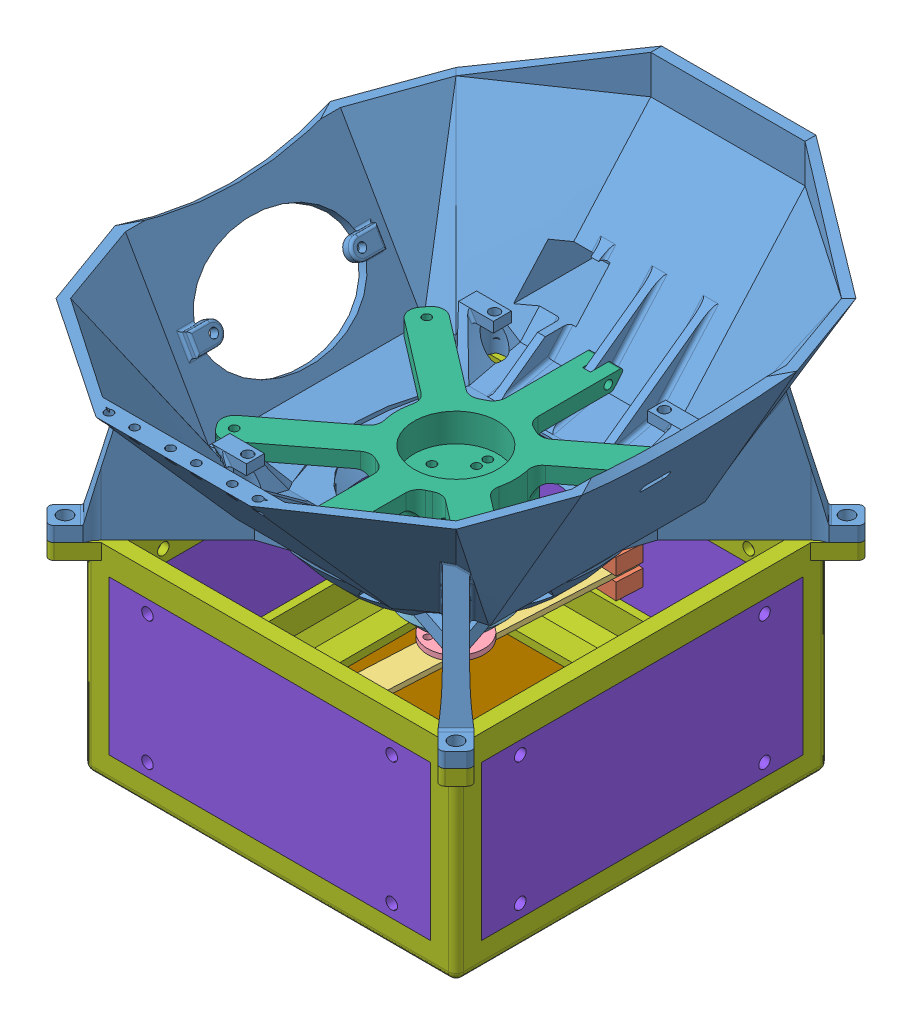
SolidWorks assembly TopFrameWithFlywheel_V1_CN, configuration Défaut. Lengths in mm.
Overall size (181.59 173.79 220.01).
16 component instances, 9 part files, 20 mates.
Components (placement in the parent):
- TopFrame_V1_CN_InProgress-1: TopFrame_V1_CN_InProgress [Default] at origin size (181.59 93.79 220.01)
- Flywheel_CN_V2-1: Flywheel_CN_V2 [Default] at (-0.05 -30.5 0) x (-0.998597 0 -0.052958) z (0 -1 0) size (15 125 14.7)
  - PlaqueEpaisseFlywheel_CN_V2-1: PlaqueEpaisseFlywheel_CN_V2 [Default] at (0 57.5 1) size (15 10 6.35)
  - PlaqueMinceFlywheel_CN_V2-1: PlaqueMinceFlywheel_CN_V2 [Default] x (-1 0 0) z (0 0 -1) size (11.7 125 2)
  - PlaqueEpaisseFlywheel_CN_V2-2: PlaqueEpaisseFlywheel_CN_V2 [Default] at (0 -57.5 -1) x (-1 0 0) z (0 0 -1) size (15 10 6.35)
  - PlaqueEpaisseFlywheel_CN_V2-3: PlaqueEpaisseFlywheel_CN_V2 [Default] at (0 -57.5 7.35) x (-1 0 0) z (0 0 -1) size (15 10 6.35)
  - PlaqueEpaisseFlywheel_CN_V2-4: PlaqueEpaisseFlywheel_CN_V2 [Default] at (0 57.5 -1) x (-1 0 0) z (0 0 -1) size (15 10 6.35)
- FlywheelFlangeCoupling_V1_LC-1: FlywheelFlangeCoupling_V1_LC [Default] at (-0.05 -27.5 0) x (-0.876308 0 -0.481751) z (-0.481751 0 0.876308) size (22 10 22)
- FlywheelMotor_LCV_V2.smg-1: FlywheelMotor_LCV_V2.smg [Défaut] at (-0.05 -19.5 0) x (-0.962797 0 -0.270225) z (0 1 0) size (37.5 37.5 33)
- MotorHolder_V1_LCV-1: MotorHolder_V1_LCV [Default] at (-0.05 32.5 0) size (109.1 26 117.33)
- AcrylicCage_V1_CN-1: AcrylicCage_V1_CN [Défaut] at (0 6.2197 0) x (1 0 0) z (0 0 -1) size (164.56 80 164.56)
- AcrylicPlaqueSide1_V1_CN-1: AcrylicPlaqueSide1_V1_CN [Défaut] at (-69.325 -33.7803 0) x (0 0 1) z (-1 0 0) size (125 60 3.17)
- AcrylicPlaqueSide1_V1_CN-2: AcrylicPlaqueSide1_V1_CN [Défaut] at (0 -33.7803 -69.325) x (-1 0 0) z (0 0 -1) size (125 60 3.17)
- AcrylicPlaqueSide1_V1_CN-3: AcrylicPlaqueSide1_V1_CN [Défaut] at (69.325 -33.7803 0) x (0 0 -1) z (1 0 0) size (125 60 3.17)
- AcrylicPlaqueSide1_V1_CN-4: AcrylicPlaqueSide1_V1_CN [Défaut] at (0 -33.7803 69.325) size (125 60 3.17)
- AcrylicPlaqueTop_V1_CN-1: AcrylicPlaqueTop_V1_CN [Défaut] at (0 -73.7803 0) x (1 0 0) z (0 1 0) size (125 125 3.17)
Mates (geometry in assembly coordinates):
- Coincident1: coincident anti-aligned: circle of TopFrame_V1_CN_InProgress-1; circle of MotorHolder_V1_LCV-1
- Coincident2: coincident aligned: circle of TopFrame_V1_CN_InProgress-1; circle of MotorHolder_V1_LCV-1
- Concentric1: concentric anti-aligned: circle of FlywheelMotor_LCV_V2.smg-1; circle of MotorHolder_V1_LCV-1
- Coincident3: coincident anti-aligned: plane of FlywheelMotor_LCV_V2.smg-1 through (-0.05 9.5 0) normal (0 1 0); plane of MotorHolder_V1_LCV-1 through (-0.05 9.5 0) normal (0 -1 0)
- Coincident4: coincident anti-aligned: plane of FlywheelFlangeCoupling_V1_LC-1 through (-0.05 -19.5 0) normal (0 1 0); plane of FlywheelMotor_LCV_V2.smg-1 through (-0.05 -19.5 0) normal (0 -1 0)
- Concentric2: concentric anti-aligned: circle of FlywheelFlangeCoupling_V1_LC-1; circle of FlywheelMotor_LCV_V2.smg-1
- Concentric3: concentric aligned: circle of Flywheel_CN_V2-1/PlaqueMinceFlywheel_CN_V2-1; circle of FlywheelFlangeCoupling_V1_LC-1
- Coincident6: coincident anti-aligned: plane of Flywheel_CN_V2-1/PlaqueMinceFlywheel_CN_V2-1 through (-0.05 -29.5 0) normal (0 1 0); plane of FlywheelFlangeCoupling_V1_LC-1 through (-0.05 -29.5 0) normal (0 -1 0)
- Coincident7: coincident anti-aligned: circle of TopFrame_V1_CN_InProgress-1; circle of AcrylicCage_V1_CN-1
- Concentric6: concentric anti-aligned: circle of TopFrame_V1_CN_InProgress-1; circle of AcrylicCage_V1_CN-1
- Coincident10: coincident aligned: circle of AcrylicCage_V1_CN-1; circle of AcrylicPlaqueSide1_V1_CN-4
- Concentric7: concentric aligned: circle of AcrylicCage_V1_CN-1; circle of AcrylicPlaqueSide1_V1_CN-4
- Coincident12: coincident aligned: circle of AcrylicCage_V1_CN-1; circle of AcrylicPlaqueSide1_V1_CN-1
- Concentric9: concentric anti-aligned: circle of AcrylicCage_V1_CN-1; circle of AcrylicPlaqueSide1_V1_CN-1
- Coincident15: coincident aligned: circle of AcrylicCage_V1_CN-1; circle of AcrylicPlaqueSide1_V1_CN-2
- Concentric10: concentric aligned: circle of AcrylicCage_V1_CN-1; circle of AcrylicPlaqueSide1_V1_CN-2
- Coincident17: coincident aligned: circle of AcrylicCage_V1_CN-1; circle of AcrylicPlaqueSide1_V1_CN-3
- Coincident18: coincident aligned: cylinder of AcrylicCage_V1_CN-1 through (-82.2782 -58.7803 47.5) axis (1 0 0) radius 2.25; circle of AcrylicPlaqueSide1_V1_CN-3
- Coincident19: coincident anti-aligned: circle of AcrylicCage_V1_CN-1; circle of AcrylicPlaqueTop_V1_CN-1
- Coincident21: coincident anti-aligned: circle of AcrylicCage_V1_CN-1; circle of AcrylicPlaqueTop_V1_CN-1
